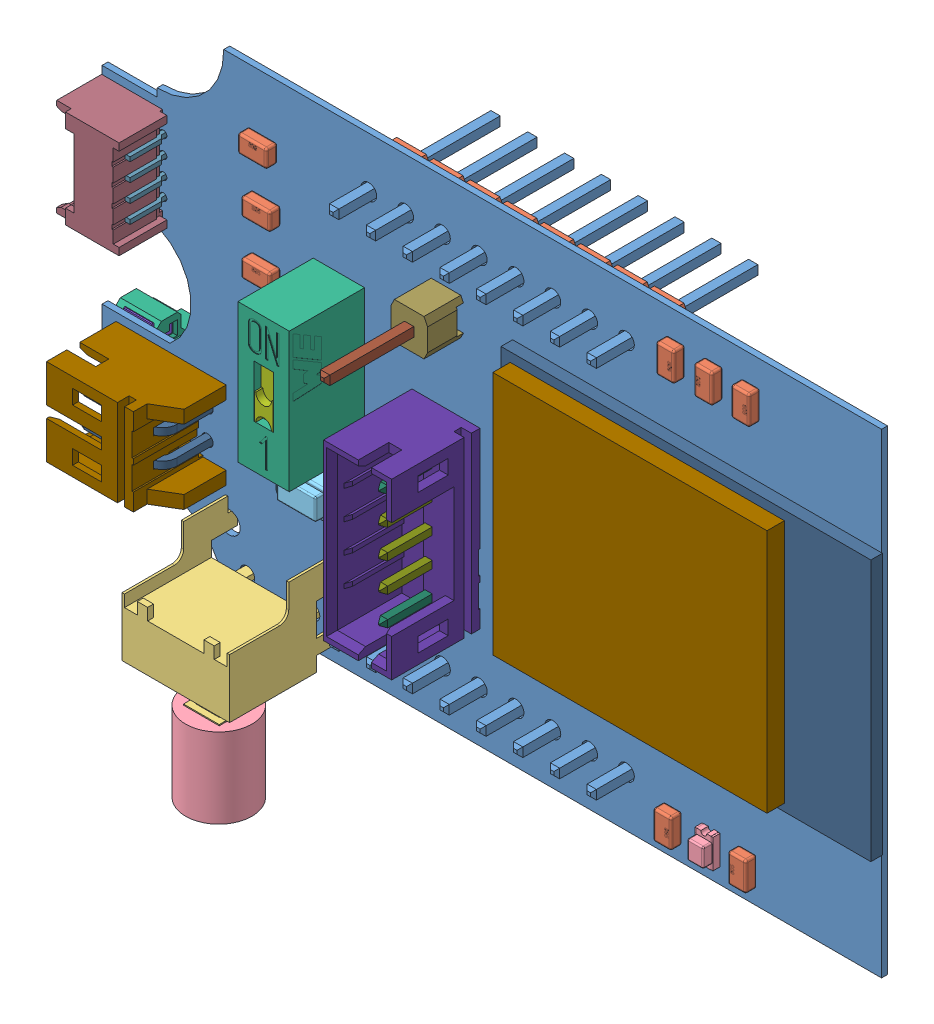
SolidWorks assembly magic_arm_2_PCB_18_9, configuration Default. Lengths in mm.
Overall size (53.86 40.67 17.49).
122 component instances, 29 part files, 0 mates.
Components (placement in the parent):
- Board-1: Board [Default] at (0 0 -0.4115) size (53.8 32.8 0.41)
- R3_1-1: R3_1 [Default] at origin size (2 1.25 0.78)
  - SW3dPS-0805_SMD_Resistor-1: SW3dPS-0805_SMD_Resistor [Default] at (7.3406 28.4735 0.0153) x (1 0 0) z (0 -1 0) size (2 0.78 1.25)
- R4_1-1: R4_1 [Default] at origin size (2 1.25 0.78)
  - SW3dPS-0805_SMD_Resistor-1: SW3dPS-0805_SMD_Resistor [Default] at (7.5692 24.8159 0.0153) x (1 0 0) z (0 -1 0) size (2 0.78 1.25)
- R5_1-1: R5_1 [Default] at origin size (2 1.25 0.78)
  - SW3dPS-0805_SMD_Resistor-1: SW3dPS-0805_SMD_Resistor [Default] at (7.5692 21.1329 0.0153) x (1 0 0) z (0 -1 0) size (2 0.78 1.25)
- SW2-1: SW2 [Default] at origin size (8.94 14.17 10.62)
  - User_Library-omron_b3f-3152-1: User_Library-omron_b3f-3152 [Default] at (8.4782 -0.0509 4.191) x (1 0 0) z (0 -1 0) size (8.94 10.62 10.36)
  - 75857376-1: 75857376 [Default] at (8.4491 -2.3623 4.191) x (1 0 0) z (0 -1 0) size (4.57 4.57 5.51)
    - Cylinder-1: Cylinder [Default] at origin size (4.57 4.57 5.51)
- R13-1: R13 [Default] at origin size (2 1.25 0.78)
  - SW3dPS-0805_SMD_Resistor-1: SW3dPS-0805_SMD_Resistor [Default] at (33.1216 12.5647 -0.4268) x (-1 0 0) z (0 -1 0) size (2 0.78 1.25)
- R12-1: R12 [Default] at origin size (2 1.25 0.78)
  - SW3dPS-0805_SMD_Resistor-1: SW3dPS-0805_SMD_Resistor [Default] at (33.1216 17.6867 -0.4268) x (1 0 0) z (0 1 0) size (2 0.78 1.25)
- R11-1: R11 [Default] at origin size (2 1.25 0.78)
  - SW3dPS-0805_SMD_Resistor-1: SW3dPS-0805_SMD_Resistor [Default] at (33.1216 7.3913 -0.4268) x (1 0 0) z (0 1 0) size (2 0.78 1.25)
- R10-1: R10 [Default] at origin size (1.25 2 0.78)
  - SW3dPS-0805_SMD_Resistor-1: SW3dPS-0805_SMD_Resistor [Default] at (40.7923 2.0828 0.0153) x (0 1 0) z (1 0 0) size (2 0.78 1.25)
- Q7-1: Q7 [Default] at origin size (2.5 3 1.1)
  - SW3DPS-SOT-23-DEFAULT-1: SW3DPS-SOT-23-DEFAULT [Default] at (25.5271 19.2533 -0.9195) x (0 -1 0) z (1 0 0) size (3 1.1 2.5)
- Q6_1-1: Q6_1 [Default] at origin size (2.5 3 1.1)
  - SW3DPS-SOT-23-DEFAULT-1: SW3DPS-SOT-23-DEFAULT [Default] at (25.5271 11.2523 -0.9195) x (0 -1 0) z (1 0 0) size (3 1.1 2.5)
- Q5_1-1: Q5_1 [Default] at origin size (3 2.5 1.1)
  - SW3DPS-SOT-23-DEFAULT-1: SW3DPS-SOT-23-DEFAULT [Default] at (17.3735 7.2899 -0.9195) x (1 0 0) z (0 1 0) size (3 1.1 2.5)
- J5-1: J5 [Default] at origin size (5.4 7.25 3.41)
  - 653102131822-1: 653102131822 [Default] at (-1.6762 9.8799 -2.1415) x (0 1 0) z (0 0 -1) size (7.25 5.4 3.41)
    - 653102131822-1: 653102131822 [Default] at origin size (7.25 4.2 3.4)
    - 6531xx131822_PIN-1: 6531xx131822_PIN [Default] at (-0.625 2.7 -0.425) x (1 0 0) z (0 -1 0) size (0.3 1.48 4.54)
    - 6531xx131822_PIN-2: 6531xx131822_PIN [Default] at (0.625 2.7 -0.425) x (1 0 0) z (0 -1 0) size (0.3 1.48 4.54)
    - 6531xx131822_PIN_FLANGE-1: 6531xx131822_PIN_FLANGE [Default] at (2.5 -0.095 -1.05) size (1.25 1.95 1.4)
    - 6531xx131822_PIN_FLANGE-2: 6531xx131822_PIN_FLANGE [Default] at (-2.5 -0.095 -1.05) x (-1 0 0) z (0 0 1) size (1.25 1.95 1.4)
- J4-1: J4 [Default] at origin size (7.6 6 8.09)
  - 62000211722-1: 62000211722 [Default] at (0.2161 9.8799 2.45) x (0 1 0) z (-1 0 0) size (6 8.09 7.6)
    - 62000211722-1: 62000211722 [Default] at origin size (6 4.8 7.6)
    - 6200xx11722_PIN1-1: 6200xx11722_PIN1 [Default] at (-1 1.645 -0.05) size (0.5 6.59 5.9)
    - 6200xx11722_PIN1-2: 6200xx11722_PIN1 [Default] at (1 1.645 -0.05) size (0.5 6.59 5.9)
- C3_1-1: C3_1 [Default] at origin size (2.54 2.54 11.54)
  - 61300111121-1: 61300111121 [Default] at (19.9391 25.0191 1.27) x (1 0 0) z (0 -1 0) size (2.54 11.54 2.54)
    - 6130xx11121_PIN-1: 6130xx11121_PIN [Default] at (0 1.5 0) x (1 0 0) z (0 -1 0) size (0.64 0.64 11.54)
    - 61300111121-1: 61300111121 [Default] at origin size (2.54 2.54 2.54)
- R15-1: R15 [Default] at origin size (1.25 2 0.78)
  - SW3dPS-0805_SMD_Resistor-1: SW3dPS-0805_SMD_Resistor [Default] at (41.0211 30.0736 0.0153) x (0 -1 0) z (-1 0 0) size (2 0.78 1.25)
- J1_1-1: J1_1 [Default] at origin size (4.7 6.75 5.8)
  - 653004117322-1: 653004117322 [Default] at (-1.4261 23.7749 1.8) x (0 1 0) z (-1 0 0) size (6.75 5.8 4.7)
    - 653004117322-1: 653004117322 [Default] at origin size (6.75 3.5 4.7)
    - 6530xx117322_PIN-1: 6530xx117322_PIN [Default] at (-1.875 0.375 -1.96) size (0.3 4.9 4)
    - 6530xx117322_PIN-2: 6530xx117322_PIN [Default] at (-0.625 0.375 -1.96) size (0.3 4.9 4)
    - 6530xx117322_PIN-3: 6530xx117322_PIN [Default] at (0.625 0.375 -1.96) size (0.3 4.9 4)
    - 6530xx117322_PIN-4: 6530xx117322_PIN [Default] at (1.875 0.375 -1.96) size (0.3 4.9 4)
- J3-1: J3 [Default] at origin size (4.7 12 9.5)
  - 62000511622-1: 62000511622 [Default] at (19.99 13.0555 3.1) x (0 1 0) z (0 0 1) size (12 4.7 9.5)
    - Pin1-1: Pin1 [Default] at (-4 -0.35 -3.88) x (0 1 0) z (0 0 1) size (0.77 0.5 8.62)
    - Pin1-2: Pin1 [Default] at (4 -0.35 -3.88) x (0 1 0) z (0 0 1) size (0.77 0.5 8.62)
    - Pin2-1: Pin2 [Default] at (-2 -0.85 -6.45) x (0 -1 0) z (0 0 1) size (0.5 0.5 8.62)
    - Pin2-2: Pin2 [Default] at (0 -0.85 -6.45) x (0 -1 0) z (0 0 1) size (0.5 0.5 8.62)
    - Pin2-3: Pin2 [Default] at (2 -0.85 -6.45) x (0 -1 0) z (0 0 1) size (0.5 0.5 8.62)
    - 62000511622-1: 62000511622 [Default] at origin size (12 4.7 6.1)
- Q1_1-1: Q1_1 [Default] at origin size (4 5 1.75)
  - 76846376-1: 76846376 [Default] at (7.0866 26.0858 -2.1615) size (4 5 1.75)
    - Extruded-1: Extruded [Default] at origin size (4 5 1.75)
- C1_1-1: C1_1 [Default] at origin size (20.32 2.54 11.54)
  - 61300811121-1: 61300811121 [Default] at (23.5001 29.2999 -1.6815) x (1 0 0) z (0 1 0) size (20.32 11.54 2.54)
    - 6130xx11121_PIN_2-1: 6130xx11121_PIN_2 [Default] at (-8.89 1.5 0) x (1 0 0) z (0 -1 0) size (0.64 0.64 11.54)
    - 6130xx11121_PIN_2-2: 6130xx11121_PIN_2 [Default] at (-6.35 1.5 0) x (1 0 0) z (0 -1 0) size (0.64 0.64 11.54)
    - 6130xx11121_PIN_2-3: 6130xx11121_PIN_2 [Default] at (-3.81 1.5 0) x (1 0 0) z (0 -1 0) size (0.64 0.64 11.54)
    - 6130xx11121_PIN_2-4: 6130xx11121_PIN_2 [Default] at (-1.27 1.5 0) x (1 0 0) z (0 -1 0) size (0.64 0.64 11.54)
    - 6130xx11121_PIN_2-5: 6130xx11121_PIN_2 [Default] at (1.27 1.5 0) x (1 0 0) z (0 -1 0) size (0.64 0.64 11.54)
    - 6130xx11121_PIN_2-6: 6130xx11121_PIN_2 [Default] at (3.81 1.5 0) x (1 0 0) z (0 -1 0) size (0.64 0.64 11.54)
    - 6130xx11121_PIN_2-7: 6130xx11121_PIN_2 [Default] at (6.35 1.5 0) x (1 0 0) z (0 -1 0) size (0.64 0.64 11.54)
    - 6130xx11121_PIN_2-8: 6130xx11121_PIN_2 [Default] at (8.89 1.5 0) x (1 0 0) z (0 -1 0) size (0.64 0.64 11.54)
    - 61300811121-1: 61300811121 [Default] at origin size (20.32 2.54 2.54)
- C2_1-1: C2_1 [Default] at origin size (20.32 2.54 11.54)
  - 61300811121-1: 61300811121 [Default] at (23.5001 3.4999 -1.6815) x (1 0 0) z (0 1 0) size (20.32 11.54 2.54)
    - 6130xx11121_PIN_2-1: 6130xx11121_PIN_2 [Default] at (-8.89 1.5 0) x (1 0 0) z (0 -1 0) size (0.64 0.64 11.54)
    - 6130xx11121_PIN_2-2: 6130xx11121_PIN_2 [Default] at (-6.35 1.5 0) x (1 0 0) z (0 -1 0) size (0.64 0.64 11.54)
    - 6130xx11121_PIN_2-3: 6130xx11121_PIN_2 [Default] at (-3.81 1.5 0) x (1 0 0) z (0 -1 0) size (0.64 0.64 11.54)
    - 6130xx11121_PIN_2-4: 6130xx11121_PIN_2 [Default] at (-1.27 1.5 0) x (1 0 0) z (0 -1 0) size (0.64 0.64 11.54)
    - 6130xx11121_PIN_2-5: 6130xx11121_PIN_2 [Default] at (1.27 1.5 0) x (1 0 0) z (0 -1 0) size (0.64 0.64 11.54)
    - 6130xx11121_PIN_2-6: 6130xx11121_PIN_2 [Default] at (3.81 1.5 0) x (1 0 0) z (0 -1 0) size (0.64 0.64 11.54)
    - 6130xx11121_PIN_2-7: 6130xx11121_PIN_2 [Default] at (6.35 1.5 0) x (1 0 0) z (0 -1 0) size (0.64 0.64 11.54)
    - 6130xx11121_PIN_2-8: 6130xx11121_PIN_2 [Default] at (8.89 1.5 0) x (1 0 0) z (0 -1 0) size (0.64 0.64 11.54)
    - 61300811121-1: 61300811121 [Default] at origin size (20.32 2.54 2.54)
- J2_1-1: J2_1 [Default] at origin size (7.98 5.43 2.94)
  - Micro_USB-1: Micro_USB [Default] at (39.6115 2.4169 -1.6518) x (-1 0 0) z (0 -1 0) size (7.98 2.94 5.43)
- LED1_1-1: LED1_1 [Default] at origin size (1.25 2.02 1.1)
  - User_Library-led_0805-blue-1: User_Library-led_0805-blue [Default] at (38.2397 2.0828 0) x (0 -1 0) z (0 0 1) size (2.02 1.25 1.1)
- Q2_1-1: Q2_1 [Default] at origin size (4 5 1.75)
  - 76846376-1: 76846376 [Default] at (6.858 19.5834 -2.1615) size (4 5 1.75)
    - Extruded-1: Extruded [Default] at origin size (4 5 1.75)
- Q3_1-1: Q3_1 [Default] at origin size (2.5 3 1.1)
  - SW3DPS-SOT-23-DEFAULT-1: SW3DPS-SOT-23-DEFAULT [Default] at (15.3163 25.3239 -0.9195) x (0 -1 0) z (1 0 0) size (3 1.1 2.5)
- Q4_1-1: Q4_1 [Default] at origin size (2.5 3 1.1)
  - SW3DPS-SOT-23-DEFAULT-1: SW3DPS-SOT-23-DEFAULT [Default] at (16.7133 15.1512 -0.9195) x (0 -1 0) z (1 0 0) size (3 1.1 2.5)
- R1_1-1: R1_1 [Default] at origin size (1.25 2 0.78)
  - SW3dPS-0805_SMD_Resistor-1: SW3dPS-0805_SMD_Resistor [Default] at (35.6363 2.0828 0.0153) x (0 -1 0) z (-1 0 0) size (2 0.78 1.25)
- R2_1-1: R2_1 [Default] at origin size (1.25 2 0.78)
  - SW3dPS-0805_SMD_Resistor-1: SW3dPS-0805_SMD_Resistor [Default] at (38.4555 30.0736 0.0153) x (0 1 0) z (1 0 0) size (2 0.78 1.25)
- R7_1-1: R7_1 [Default] at origin size (1.25 2 0.78)
  - SW3dPS-0805_SMD_Resistor-1: SW3dPS-0805_SMD_Resistor [Default] at (35.8395 30.0736 0.0153) x (0 -1 0) z (-1 0 0) size (2 0.78 1.25)
- R8-1: R8 [Default] at origin size (2 1.25 0.78)
  - SW3dPS-0805_SMD_Resistor-1: SW3dPS-0805_SMD_Resistor [Default] at (25.6794 15.3417 -0.4268) x (-1 0 0) z (0 -1 0) size (2 0.78 1.25)
- R9-1: R9 [Default] at origin size (2 1.25 0.78)
  - SW3dPS-0805_SMD_Resistor-1: SW3dPS-0805_SMD_Resistor [Default] at (25.6794 7.4169 -0.4268) x (-1 0 0) z (0 -1 0) size (2 0.78 1.25)
- R14-1: R14 [Default] at origin size (2 1.25 0.78)
  - SW3dPS-0805_SMD_Resistor-1: SW3dPS-0805_SMD_Resistor [Default] at (33.1216 22.8601 -0.4268) x (-1 0 0) z (0 -1 0) size (2 0.78 1.25)
- Reset1-1: Reset1 [Default] at origin size (6.1 3.7 2.5)
  - User_Library-Button-SMD-1: User_Library-Button-SMD [Default] at (12.0903 10.9219 0) x (-1 0 0) z (0 1 0) size (6.1 2.5 3.7)
- SW1-1: SW1 [Default] at origin size (3.54 9.6 9.2)
  - 418117170901-1: 418117170901 [Default] at (12.7509 18.8215 0.2) size (3.54 9.6 9.2)
    - Base_switch-1: Base_switch [Default] at origin size (3.54 9.6 5.2)
    - clip-1: clip [Default] at (0 -0.9 4.7) size (2.3 5.8 2.9)
    - base-1: base [Default] at (0 0 0.2) size (2.54 8.7 6.2)
- R6_1-1: R6_1 [Default] at origin size (2 1.25 0.78)
  - SW3dPS-0805_SMD_Resistor-1: SW3dPS-0805_SMD_Resistor [Default] at (25.6879 22.9109 -0.4268) x (-1 0 0) z (0 -1 0) size (2 0.78 1.25)
- M1-1: M1 [Default] at origin size (25.53 18.03 2)
  - 76823120-1: 76823120 [Default] at (34.633 16.3365 0.8) size (18.92 16.89 1.2)
    - Extruded_2-1: Extruded_2 [Default] at origin size (18.92 16.89 1.2)
  - 76822984-1: 76822984 [Default] at (37.3 16.4 0) size (25.53 18.03 0.8)
    - Extruded_3-1: Extruded_3 [Default] at origin size (25.53 18.03 0.8)
- C4_1-1: C4_1 [Default] at origin size (2 1.25 0.78)
  - 0805_SMD_Capacitor-1: 0805_SMD_Capacitor [Default] at (19.685 21.3107 -0.4268) x (-1 0 0) z (0 -1 0) size (2 0.78 1.25)
